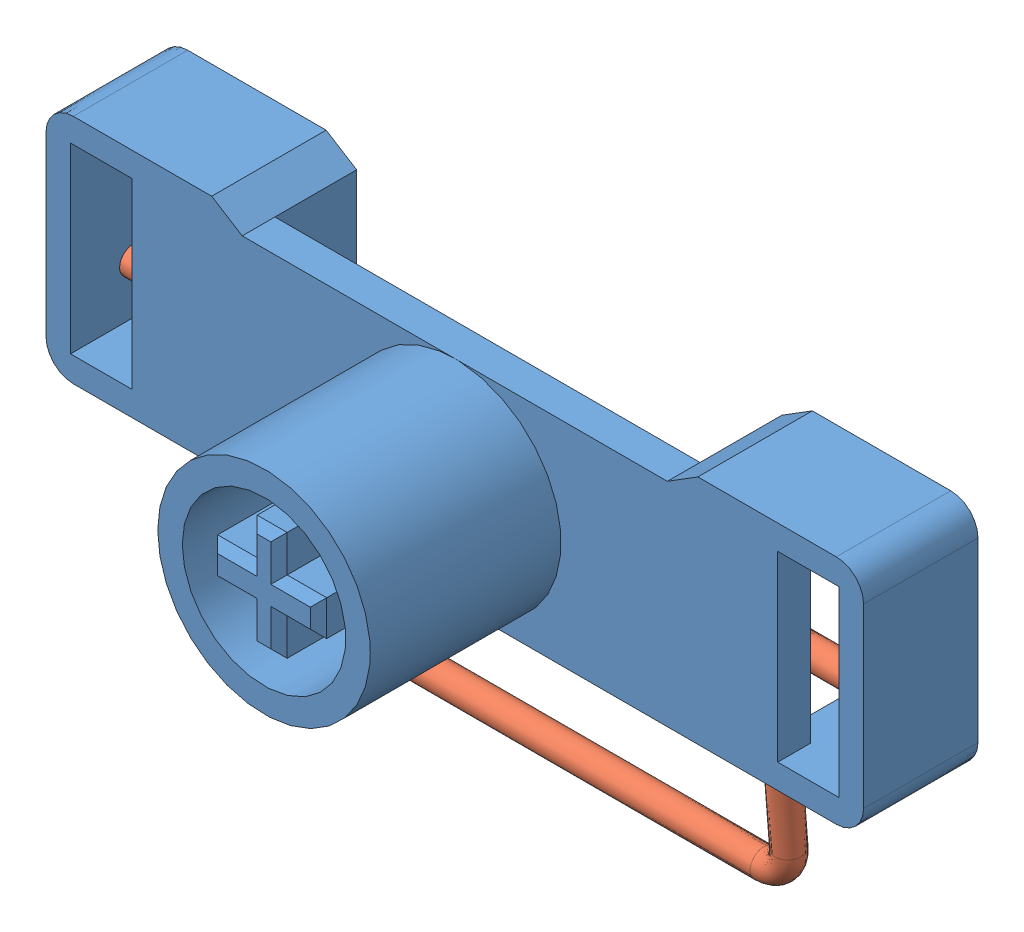
SolidWorks assembly Plunger 2.25x, configuration Default. Lengths in mm.
Overall size (30 13.92 11.2).
2 component instances, 2 part files, 5 mates.
Components (placement in the parent):
- Plunger 2.25x-1: Plunger 2.25x [Default] at origin size (30 8.5 11.2)
- Plunger String 2.25x-1: Plunger String 2.25x [Default] at (0 -0.5568 -1.7) x (1 0 0) z (0 0.997031 0.076997) size (27 1 9.25)
Mates (geometry in assembly coordinates):
- Coincident2: coincident aligned: plane of Plunger 2.25x-1 through (0 0 0) normal (1 0 0); plane of Plunger String 2.25x-1
- Tangent2: tangent anti-aligned: plane of Plunger 2.25x-1 through (0 0 -1.2) normal (0 0 -1); cylinder of Plunger String 2.25x-1 through (-13.5 -0.5568 -1.7) axis (1 0 0) radius 0.5
- Coincident5: coincident aligned: plane of Plunger 2.25x-1 through (0 0 0) normal (1 0 0); plane of Plunger String 2.25x-1
- LimitDistance1: limit distance = 1.9432 mm anti-aligned: cylinder of Plunger String 2.25x-1 through (-13.5 -0.5568 -1.7) axis (1 0 0) radius 0.5; plane of Plunger 2.25x-1 through (-14.1 -3 -3) normal (0 1 0)
- LimitDistance3: limit distance = 3.7568 mm anti-aligned: cylinder of Plunger String 2.25x-1 through (-13.5 -0.5568 -1.7) axis (1 0 0) radius 0.5; plane of Plunger 2.25x-1 through (-14.1 3.7 -3) normal (0 -1 0)
